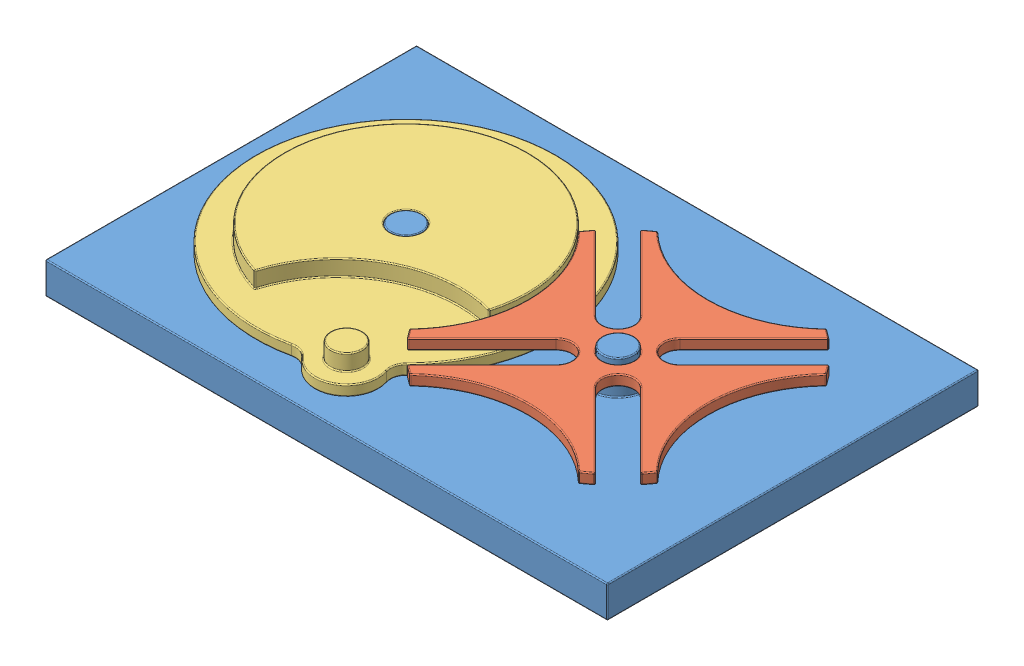
SolidWorks assembly Geneva_Drive, configuration Default. Lengths in mm.
Overall size (540.37 55 350.74).
3 component instances, 3 part files, 4 mates.
Components (placement in the parent):
- Base-1: Base [Default] at (-30.9942 40 -14.8311) x (1 0 0) z (0 1 0) size (530 350 55)
- Geneva_Star-1: Geneva_Star [Default] at (69.0058 40 85.1689) x (0 0 -1) z (0 1 0) size (233.31 233.31 10)
- Drive_Wheel-1: Drive_Wheel [Default] at (-159.0018 40 81.1667) x (-0.280077 0 0.959978) z (0 1 0) size (282.84 282.84 25)
Mates (geometry in assembly coordinates):
- Coincident1: coincident anti-aligned: circle of Base-1; plane of Geneva_Star-1 through (39.7165 40 14.4582) normal (0 -1 0)
- Concentric1: concentric anti-aligned: cylinder of Base-1 through (69.0058 97.4264 -14.8311) axis (0 -1 0) radius 15; cylinder of Geneva_Star-1 through (69.0058 30 -14.8311) axis (0 1 0) radius 15
- Concentric2: concentric anti-aligned: cylinder of Base-1 through (-130.9942 97.4264 -14.8311) axis (0 -1 0) radius 15; cylinder of Drive_Wheel-1 through (-130.9942 30 -14.8311) axis (0 1 0) radius 15
- Coincident2: coincident anti-aligned: plane of Base-1 through (234.0058 30 160.1689) normal (0 1 0); plane of Drive_Wheel-1 through (-114.2856 30 61.574) normal (0 -1 0)
